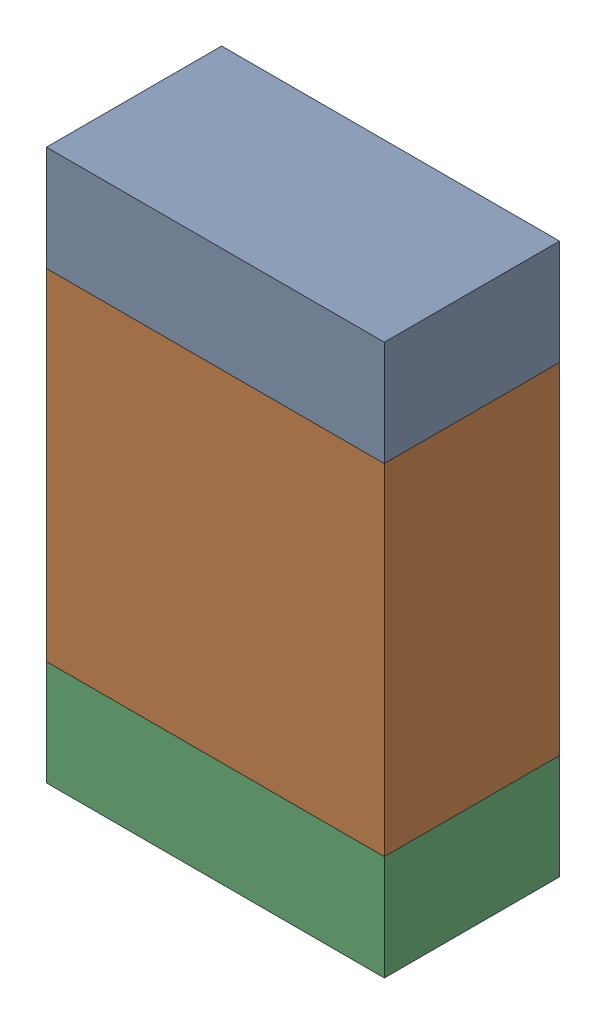
SolidWorks assembly R11-1, configuration Default. Lengths in mm.
Overall size (1.35 2.2 0.7).
6 component instances, 2 part files, 0 mates.
Components (placement in the parent):
- 959207304-1-1: 959207304-1 [Default] at (133.9849 94.0691 0) size (1.35 0.42 0.7)
  - Extruded-39-1: Extruded-39 [Default] at origin size (1.35 0.42 0.7)
- 959207440-1-1: 959207440-1 [Default] at (133.9849 93.1791 0) size (1.35 1.36 0.7)
  - Extruded-40-1: Extruded-40 [Default] at origin size (1.35 1.36 0.7)
- 959207304-1-2: 959207304-1 [Default] at (133.9849 92.2891 0) size (1.35 0.42 0.7)
  - Extruded-39-1: Extruded-39 [Default] at origin size (1.35 0.42 0.7)
